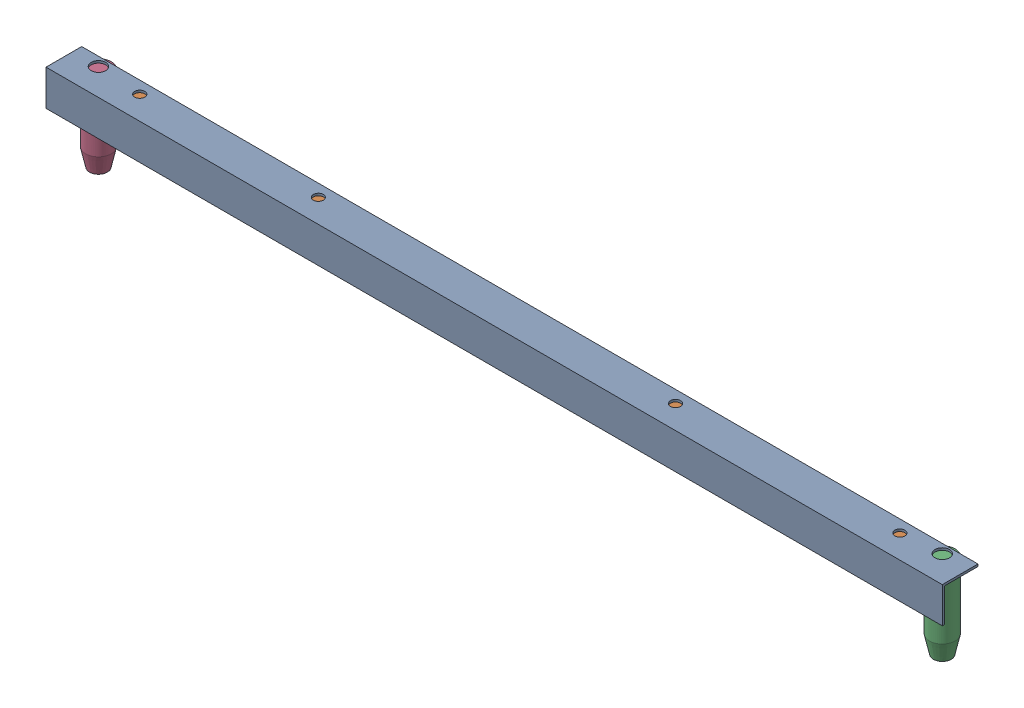
SolidWorks assembly GE-09031_ASM, configuration Default. Lengths in mm.
Overall size (1274.76 123.83 56.36).
4 component instances, 3 part files, 0 mates.
Components (placement in the parent):
- GE-09031-01-1: GE-09031-01 [Default] at origin size (1274.76 50.8 50.8)
- GE-09031-02-1: GE-09031-02 [Default] at (-0.7937 -3.175 -14.2875) size (1123.95 38.1 38.1)
- GE-09031-03-1: GE-09031-03 [Default] at (599.2812 -63.5 -38.1) x (1 0 0) z (0 -1 0) size (36.51 36.51 120.65)
- GE-09031-03-2: GE-09031-03 [Default] at (-600.8687 -63.5 -38.1) x (1 0 0) z (0 -1 0) size (36.51 36.51 120.65)
